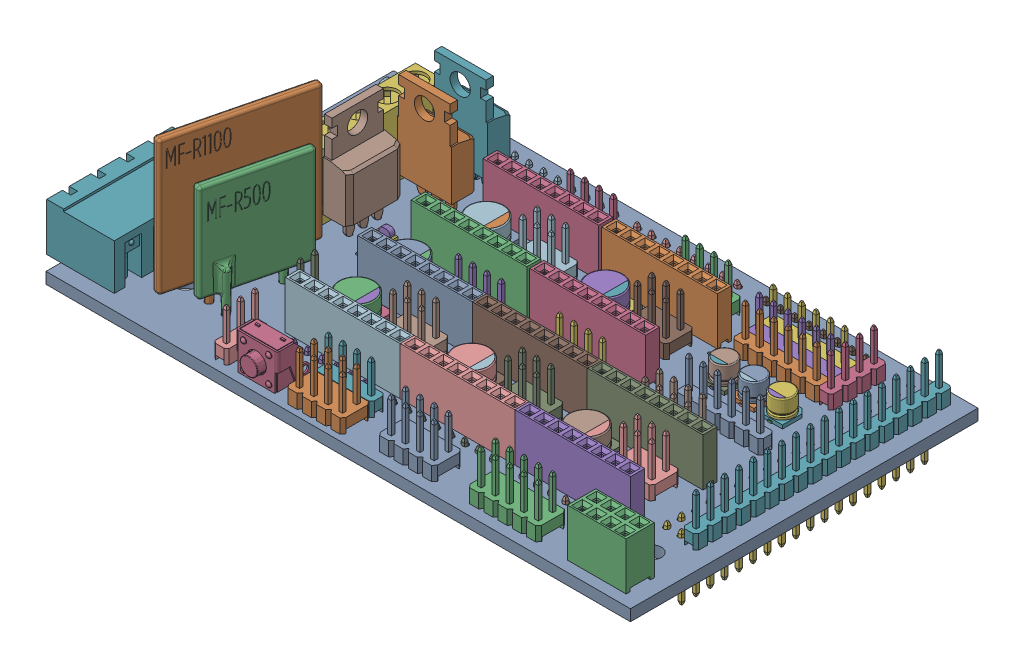
SolidWorks assembly 3-RAMPS1_4, configuration Default. Lengths in mm.
Overall size (106.38 37.63 61.76).
107 component instances, 31 part files, 0 mates.
Components (placement in the parent):
- 3-RAMPS1_4-1: 3-RAMPS1_4 [Default] at (-38.4421 2.2803 -26.502) x (1 0 0) z (0 1 0) size (103.85 61.76 2)
- 3-User Library-POWER MOSFET, NON-SURFACE-MOUNT-1: 3-User Library-POWER MOSFET, NON-SURFACE-MOUNT [Default] at (-31.1839 8.1207 -13.4695) x (-1 0 0) z (0 -1 0) size (9.65 4.5 28.38)
- 3-female_header_a-bl254-dg-g08d-1: 3-female_header_a-bl254-dg-g08d [Default] at (41.0481 4.2584 25.6311) size (10.41 11.65 5)
- 3-female_header_a-bl254-eg-g08d-2: 3-female_header_a-bl254-eg-g08d [Default] at (6.3865 4.2963 -6.1397) size (20.57 11.65 2.5)
- 3-female_header_a-bl254-eg-g08d-19: 3-female_header_a-bl254-eg-g08d [Default] at (26.827 4.2963 16.9325) size (20.57 11.65 2.5)
- 3-pin_header_aw254-dg-g36d-1: 3-pin_header_aw254-dg-g36d [Default] at (40.9113 2.2239 -7.3898) x (0 0 1) z (-1 0 0) size (45.72 11.5 5.08)
- 3-pin_header_aw140-eg-g18d-1: 3-pin_header_aw140-eg-g18d [Default] at (44.7498 4.3175 -7.3949) x (0 0 -1) z (-1 0 0) size (45.62 11.2 2.5)
- 3-pin_header_aw140-eg-g08d-1: 3-pin_header_aw140-eg-g08d [Default] at (28.1033 2.2803 19.4616) size (20.22 11.2 2.5)
- 3-pin_header_aw140-eg-g08d-2: 3-pin_header_aw140-eg-g08d [Default] at (5.0609 2.2803 19.4616) size (20.22 11.2 2.5)
- 3-pin_header_aw140-eg-g08d-3: 3-pin_header_aw140-eg-g08d [Default] at (-0.0426 2.2803 -29.0108) size (20.22 11.2 2.5)
- 3-pin_header_aw140-eg-g08d-4: 3-pin_header_aw140-eg-g08d [Default] at (22.8713 2.2803 -29.0108) size (20.22 11.2 2.5)
- 3-pin_header_aw140-eg-g08d-5: 3-pin_header_aw140-eg-g08d [Default] at (-21.773 2.2803 -29.0108) size (20.22 11.2 2.5)
- 3-pin_header_aw140-eg-g06d-1: 3-pin_header_aw140-eg-g06d [Default] at (29.4382 4.2803 -6.1813) x (-1 0 0) z (0 0 1) size (15.14 11.2 2.5)
- 3-pin_header_aw140-eg-g06d-2: 3-pin_header_aw140-eg-g06d [Default] at (26.2798 4.262 -19.3796) x (-1 0 0) z (0 0 1) size (15.14 11.2 2.5)
- 3-pin_header_aw140-eg-g04d-1: 3-pin_header_aw140-eg-g04d [Default] at (8.4073 4.2803 -24.0519) x (-1 0 0) z (0 0 1) size (10.06 11.2 2.5)
- 3-pin_header_aw140-eg-g04d-2: 3-pin_header_aw140-eg-g04d [Default] at (-12.021 4.262 -24.0519) x (-1 0 0) z (0 0 1) size (10.06 11.2 2.5)
- 3-pin_header_aw140-eg-g04d-3: 3-pin_header_aw140-eg-g04d [Default] at (-8.9039 4.262 -1.0355) x (-1 0 0) z (0 0 1) size (10.06 11.2 2.5)
- 3-pin_header_aw140-eg-g04d-4: 3-pin_header_aw140-eg-g04d [Default] at (9.0685 4.262 -1.0355) x (-1 0 0) z (0 0 1) size (10.06 11.2 2.5)
- 3-pin_header_aw140-eg-g04d-5: 3-pin_header_aw140-eg-g04d [Default] at (-8.3709 4.2803 22.5944) x (-1 0 0) z (0 0 1) size (10.06 11.2 2.5)
- 3-pin_header_aw254-dg-g06d-1: 3-pin_header_aw254-dg-g06d [Default] at (-10.2573 4.2803 9.2323) x (-1 0 0) z (0 0 1) size (7.62 11.5 5.08)
- 3-pin_header_aw254-dg-g06d-2: 3-pin_header_aw254-dg-g06d [Default] at (10.1683 4.262 9.2323) x (-1 0 0) z (0 0 1) size (7.62 11.5 5.08)
- 3-pin_header_aw254-dg-g06d-3: 3-pin_header_aw254-dg-g06d [Default] at (30.6527 4.262 9.2323) x (-1 0 0) z (0 0 1) size (7.62 11.5 5.08)
- 3-pin_header_aw254-dg-g06d-4: 3-pin_header_aw254-dg-g06d [Default] at (10.1683 4.262 -13.7827) x (-1 0 0) z (0 0 1) size (7.62 11.5 5.08)
- 3-pin_header_aw254-dg-g06d-5: 3-pin_header_aw254-dg-g06d [Default] at (-10.2204 4.262 -13.7827) x (-1 0 0) z (0 0 1) size (7.62 11.5 5.08)
- 3-pin_header_aw254-dg-g08d-1: 3-pin_header_aw254-dg-g08d [Default] at (7.0775 4.2803 25.6017) x (-1 0 0) z (0 0 1) size (10.16 11.5 5.08)
- 3-pin_header_aw254-dg-g08d-2: 3-pin_header_aw254-dg-g08d [Default] at (-8.3884 4.2803 26.4286) x (-1 0 0) z (0 0 1) size (10.16 11.5 5.08)
- 3-pin_header_aw254-dg-g10d-1: 3-pin_header_aw254-dg-g10d [Default] at (24.3252 4.2803 25.6162) x (-1 0 0) z (0 0 1) size (12.7 11.5 5.08)
- 3-pin_header_aw140-eg-g04d-6: 3-pin_header_aw140-eg-g04d [Default] at (35.1498 4.262 -23.186) x (0 0 -1) z (-1 0 0) size (10.06 11.2 2.5)
- 3-pin_header_aw140-eg-g06d-8: 3-pin_header_aw140-eg-g06d [Default] at (-15.2568 2.2803 19.3514) size (15.14 11.2 2.5)
- 3-terminal_blocks_a-tb500-to06-1: 3-terminal_blocks_a-tb500-to06 [Default] at (-37.528 4.2803 -9.8658) x (0 0 1) z (-1 0 0) size (30.6 13.8 8.3)
- 3-terminal_blocks_a-tb508-oq04ch-1: 3-terminal_blocks_a-tb508-oq04ch [Default] at (-57.4712 4.2803 16.3679) x (0 0 1) z (-1 0 0) size (22.32 12.5 12)
- 3-pin_header_aw254-dg-g08d-3: 3-pin_header_aw254-dg-g08d [Default] at (26.8817 4.262 0.2918) x (-1 0 0) z (0 0 1) size (10.16 11.5 5.08)
- 3-pin_header_aw140-eg-g02d-1: 3-pin_header_aw140-eg-g02d [Default] at (-26.0896 4.2803 12.3888) x (0 0 1) z (1 0 0) size (4.98 11.2 2.5)
- 3-pin_header_aw140-eg-g03d-1: 3-pin_header_aw140-eg-g03d [Default] at (-25.5036 4.2803 24.8649) x (0 0 1) z (1 0 0) size (7.52 11.2 2.5)
- 3-User Library-CAPSMD6_3x3_9-1: 3-User Library-CAPSMD6_3x3_9 [Default] at (-23.4034 4.2803 -13.8521) x (0 0 -1) z (0 1 0) size (6.6 7 3.91)
  - 3-User Library-CAPSMD6_3x3_9_CAP003-1: 3-User Library-CAPSMD6_3x3_9_CAP003 [Default] at origin size (0.65 2.6 0.32)
  - 3-User Library-CAPSMD6_3x3_9_CAP-1: 3-User Library-CAPSMD6_3x3_9_CAP [Default] at origin size (6.3 6.3 3.26)
  - 3-User Library-CAPSMD6_3x3_9_CAP001-1: 3-User Library-CAPSMD6_3x3_9_CAP001 [Default] at origin size (6.6 6.6 0.64)
  - 3-User Library-CAPSMD6_3x3_9_CAP002-1: 3-User Library-CAPSMD6_3x3_9_CAP002 [Default] at origin size (5.11 1.47 0.01)
  - 3-User Library-CAPSMD6_3x3_9_CAP004-1: 3-User Library-CAPSMD6_3x3_9_CAP004 [Default] at origin size (0.65 2.6 0.32)
- 3-User Library-CAPSMD6_3x3_9-2: 3-User Library-CAPSMD6_3x3_9 [Default] at (-2.2688 4.2803 -13.8521) x (0 0 -1) z (0 1 0) size (6.6 7 3.91)
  - 3-User Library-CAPSMD6_3x3_9_CAP003-1: 3-User Library-CAPSMD6_3x3_9_CAP003 [Default] at origin size (0.65 2.6 0.32)
  - 3-User Library-CAPSMD6_3x3_9_CAP-1: 3-User Library-CAPSMD6_3x3_9_CAP [Default] at origin size (6.3 6.3 3.26)
  - 3-User Library-CAPSMD6_3x3_9_CAP001-1: 3-User Library-CAPSMD6_3x3_9_CAP001 [Default] at origin size (6.6 6.6 0.64)
  - 3-User Library-CAPSMD6_3x3_9_CAP002-1: 3-User Library-CAPSMD6_3x3_9_CAP002 [Default] at origin size (5.11 1.47 0.01)
  - 3-User Library-CAPSMD6_3x3_9_CAP004-1: 3-User Library-CAPSMD6_3x3_9_CAP004 [Default] at origin size (0.65 2.6 0.32)
- 3-User Library-CAPSMD6_3x3_9-3: 3-User Library-CAPSMD6_3x3_9 [Default] at (-2.8787 4.2803 9.2865) x (0 0 -1) z (0 1 0) size (6.6 7 3.91)
  - 3-User Library-CAPSMD6_3x3_9_CAP003-1: 3-User Library-CAPSMD6_3x3_9_CAP003 [Default] at origin size (0.65 2.6 0.32)
  - 3-User Library-CAPSMD6_3x3_9_CAP-1: 3-User Library-CAPSMD6_3x3_9_CAP [Default] at origin size (6.3 6.3 3.26)
  - 3-User Library-CAPSMD6_3x3_9_CAP001-1: 3-User Library-CAPSMD6_3x3_9_CAP001 [Default] at origin size (6.6 6.6 0.64)
  - 3-User Library-CAPSMD6_3x3_9_CAP002-1: 3-User Library-CAPSMD6_3x3_9_CAP002 [Default] at origin size (5.11 1.47 0.01)
  - 3-User Library-CAPSMD6_3x3_9_CAP004-1: 3-User Library-CAPSMD6_3x3_9_CAP004 [Default] at origin size (0.65 2.6 0.32)
- 3-User Library-CAPSMD6_3x3_9-4: 3-User Library-CAPSMD6_3x3_9 [Default] at (-23.2996 4.2803 9.2865) x (0 0 -1) z (0 1 0) size (6.6 7 3.91)
  - 3-User Library-CAPSMD6_3x3_9_CAP003-1: 3-User Library-CAPSMD6_3x3_9_CAP003 [Default] at origin size (0.65 2.6 0.32)
  - 3-User Library-CAPSMD6_3x3_9_CAP-1: 3-User Library-CAPSMD6_3x3_9_CAP [Default] at origin size (6.3 6.3 3.26)
  - 3-User Library-CAPSMD6_3x3_9_CAP001-1: 3-User Library-CAPSMD6_3x3_9_CAP001 [Default] at origin size (6.6 6.6 0.64)
  - 3-User Library-CAPSMD6_3x3_9_CAP002-1: 3-User Library-CAPSMD6_3x3_9_CAP002 [Default] at origin size (5.11 1.47 0.01)
  - 3-User Library-CAPSMD6_3x3_9_CAP004-1: 3-User Library-CAPSMD6_3x3_9_CAP004 [Default] at origin size (0.65 2.6 0.32)
- 3-User Library-CAPSMD6_3x3_9-5: 3-User Library-CAPSMD6_3x3_9 [Default] at (17.5196 4.2803 9.2865) x (0 0 -1) z (0 1 0) size (6.6 7 3.91)
  - 3-User Library-CAPSMD6_3x3_9_CAP003-1: 3-User Library-CAPSMD6_3x3_9_CAP003 [Default] at origin size (0.65 2.6 0.32)
  - 3-User Library-CAPSMD6_3x3_9_CAP-1: 3-User Library-CAPSMD6_3x3_9_CAP [Default] at origin size (6.3 6.3 3.26)
  - 3-User Library-CAPSMD6_3x3_9_CAP001-1: 3-User Library-CAPSMD6_3x3_9_CAP001 [Default] at origin size (6.6 6.6 0.64)
  - 3-User Library-CAPSMD6_3x3_9_CAP002-1: 3-User Library-CAPSMD6_3x3_9_CAP002 [Default] at origin size (5.11 1.47 0.01)
  - 3-User Library-CAPSMD6_3x3_9_CAP004-1: 3-User Library-CAPSMD6_3x3_9_CAP004 [Default] at origin size (0.65 2.6 0.32)
- 3-User Library-CAPSMD6_3x3_9-6: 3-User Library-CAPSMD6_3x3_9 [Default] at (-24.6073 4.2803 -1.0117) x (0 0 -1) z (0 1 0) size (6.6 7 3.91)
  - 3-User Library-CAPSMD6_3x3_9_CAP003-1: 3-User Library-CAPSMD6_3x3_9_CAP003 [Default] at origin size (0.65 2.6 0.32)
  - 3-User Library-CAPSMD6_3x3_9_CAP-1: 3-User Library-CAPSMD6_3x3_9_CAP [Default] at origin size (6.3 6.3 3.26)
  - 3-User Library-CAPSMD6_3x3_9_CAP001-1: 3-User Library-CAPSMD6_3x3_9_CAP001 [Default] at origin size (6.6 6.6 0.64)
  - 3-User Library-CAPSMD6_3x3_9_CAP002-1: 3-User Library-CAPSMD6_3x3_9_CAP002 [Default] at origin size (5.11 1.47 0.01)
  - 3-User Library-CAPSMD6_3x3_9_CAP004-1: 3-User Library-CAPSMD6_3x3_9_CAP004 [Default] at origin size (0.65 2.6 0.32)
- 3-User Library-CAPSMD4x3_9-1: 3-User Library-CAPSMD4x3_9 [Default] at (22.2937 4.2803 -15.1178) x (1 0 0) z (0 1 0) size (4.3 4.6 3.91)
  - 3-User Library-CAPSMD4x3_9_CAPSMD4x3_9003-1: 3-User Library-CAPSMD4x3_9_CAPSMD4x3_9003 [Default] at origin size (0.65 1.8 0.32)
  - 3-User Library-CAPSMD4x3_9_CAPSMD4x3_9004-1: 3-User Library-CAPSMD4x3_9_CAPSMD4x3_9004 [Default] at origin size (0.65 1.8 0.32)
  - 3-User Library-CAPSMD4x3_9_CAPSMD4x3_9002-1: 3-User Library-CAPSMD4x3_9_CAPSMD4x3_9002 [Default] at origin size (3.12 0.9 0.01)
  - 3-User Library-CAPSMD4x3_9_CAPSMD4x3_9001-1: 3-User Library-CAPSMD4x3_9_CAPSMD4x3_9001 [Default] at origin size (4 4 3.26)
  - 3-User Library-CAPSMD4x3_9_CAPSMD4x3_9-1: 3-User Library-CAPSMD4x3_9_CAPSMD4x3_9 [Default] at origin size (4.3 4.3 0.64)
- 3-User Library-CAPSMD4x3_9-2: 3-User Library-CAPSMD4x3_9 [Default] at (27.5508 4.2803 -15.1178) x (1 0 0) z (0 1 0) size (4.3 4.6 3.91)
  - 3-User Library-CAPSMD4x3_9_CAPSMD4x3_9003-1: 3-User Library-CAPSMD4x3_9_CAPSMD4x3_9003 [Default] at origin size (0.65 1.8 0.32)
  - 3-User Library-CAPSMD4x3_9_CAPSMD4x3_9004-1: 3-User Library-CAPSMD4x3_9_CAPSMD4x3_9004 [Default] at origin size (0.65 1.8 0.32)
  - 3-User Library-CAPSMD4x3_9_CAPSMD4x3_9002-1: 3-User Library-CAPSMD4x3_9_CAPSMD4x3_9002 [Default] at origin size (3.12 0.9 0.01)
  - 3-User Library-CAPSMD4x3_9_CAPSMD4x3_9001-1: 3-User Library-CAPSMD4x3_9_CAPSMD4x3_9001 [Default] at origin size (4 4 3.26)
  - 3-User Library-CAPSMD4x3_9_CAPSMD4x3_9-1: 3-User Library-CAPSMD4x3_9_CAPSMD4x3_9 [Default] at origin size (4.3 4.3 0.64)
- 3-User Library-CAPSMD4x3_9-3: 3-User Library-CAPSMD4x3_9 [Default] at (32.6212 4.2803 -15.1178) x (1 0 0) z (0 1 0) size (4.3 4.6 3.91)
  - 3-User Library-CAPSMD4x3_9_CAPSMD4x3_9003-1: 3-User Library-CAPSMD4x3_9_CAPSMD4x3_9003 [Default] at origin size (0.65 1.8 0.32)
  - 3-User Library-CAPSMD4x3_9_CAPSMD4x3_9004-1: 3-User Library-CAPSMD4x3_9_CAPSMD4x3_9004 [Default] at origin size (0.65 1.8 0.32)
  - 3-User Library-CAPSMD4x3_9_CAPSMD4x3_9002-1: 3-User Library-CAPSMD4x3_9_CAPSMD4x3_9002 [Default] at origin size (3.12 0.9 0.01)
  - 3-User Library-CAPSMD4x3_9_CAPSMD4x3_9001-1: 3-User Library-CAPSMD4x3_9_CAPSMD4x3_9001 [Default] at origin size (4 4 3.26)
  - 3-User Library-CAPSMD4x3_9_CAPSMD4x3_9-1: 3-User Library-CAPSMD4x3_9_CAPSMD4x3_9 [Default] at origin size (4.3 4.3 0.64)
- 3-User Library-APA3010GCCK_GREEN-1: 3-User Library-APA3010GCCK_GREEN [Default] at (-34.2243 4.3303 -27.7242) x (0 0 1) z (-1 0 0) size (3 2 1)
- 3-User Library-APA3010GCCK_RED-1: 3-User Library-APA3010GCCK_RED [Default] at (-49.6191 4.3303 -27.7242) x (0 0 1) z (-1 0 0) size (3 2 1)
- 3-User Library-APA3010GCCK_RED-2: 3-User Library-APA3010GCCK_RED [Default] at (-52.1602 4.3303 -27.7242) x (0 0 1) z (-1 0 0) size (3 2 1)
- 3-User Library-MF-R1100___ _________-1: 3-User Library-MF-R1100___ _________ [Default] at (-35.7942 -0.3428 15.0699) x (0 0 -1) z (0 -1 0) size (23.64 7.06 35.7)
- 3-User Library-MF-R500___ _________-1: 3-User Library-MF-R500___ _________ [Default] at (-32.5552 -0.5896 15.3075) x (0 0 -1) z (0 -1 0) size (17.04 5.43 29.1)
- 3-User Library-SWITCH, TACTILE, RIGHT ANGLE, 12VDC, 50MA, 6_85MM ACTUATOR, WEALTH METAL TC-0244Z-1: 3-User Library-SWITCH, TACTILE, RIGHT ANGLE, 12VDC, 50MA, 6_85MM ACTUATOR, WEALTH METAL TC-0244Z [Default] at (-19.0613 3.9803 23.5512) size (7.4 11 8)
- 3-User Library-APA3010GCCK_RED-3: 3-User Library-APA3010GCCK_RED [Default] at (-29.5185 4.3303 -5.1301) size (3 2 1)
- 3-User Library-POWER MOSFET, NON-SURFACE-MOUNT-2: 3-User Library-POWER MOSFET, NON-SURFACE-MOUNT [Default] at (-31.3941 8.433 -20.0341) x (-1 0 0) z (0 -1 0) size (9.65 4.5 28.38)
- 3-User Library-POWER MOSFET, NON-SURFACE-MOUNT-3: 3-User Library-POWER MOSFET, NON-SURFACE-MOUNT [Default] at (-36.1067 8.2823 -5.2135) x (0 0 -1) z (0 -1 0) size (9.65 4.5 28.38)
- 3-female_header_a-bl254-eg-g08d-20: 3-female_header_a-bl254-eg-g08d [Default] at (26.827 4.2963 4.0825) size (20.57 11.65 2.5)
- 3-female_header_a-bl254-eg-g08d-21: 3-female_header_a-bl254-eg-g08d [Default] at (6.417 4.2963 16.9325) size (20.57 11.65 2.5)
- 3-female_header_a-bl254-eg-g08d-22: 3-female_header_a-bl254-eg-g08d [Default] at (6.417 4.2963 4.0825) size (20.57 11.65 2.5)
- 3-female_header_a-bl254-eg-g08d-23: 3-female_header_a-bl254-eg-g08d [Default] at (-13.993 4.2963 16.9325) size (20.57 11.65 2.5)
- 3-female_header_a-bl254-eg-g08d-24: 3-female_header_a-bl254-eg-g08d [Default] at (-13.993 4.2963 4.0825) size (20.57 11.65 2.5)
- 3-female_header_a-bl254-eg-g08d-16: 3-female_header_a-bl254-eg-g08d [Default] at (6.3865 4.2963 -18.9097) size (20.57 11.65 2.5)
- 3-female_header_a-bl254-eg-g08d-17: 3-female_header_a-bl254-eg-g08d [Default] at (-14.6935 4.2963 -6.1397) size (20.57 11.65 2.5)
- 3-female_header_a-bl254-eg-g08d-18: 3-female_header_a-bl254-eg-g08d [Default] at (-14.6935 4.2963 -18.9097) size (20.57 11.65 2.5)
- 3-pin_header_aw140-eg-g06d-6: 3-pin_header_aw140-eg-g06d [Default] at (26.2798 4.262 -21.8496) x (-1 0 0) z (0 0 1) size (15.14 11.2 2.5)
- 3-pin_header_aw140-eg-g06d-7: 3-pin_header_aw140-eg-g06d [Default] at (26.2798 4.262 -24.3196) x (-1 0 0) z (0 0 1) size (15.14 11.2 2.5)
